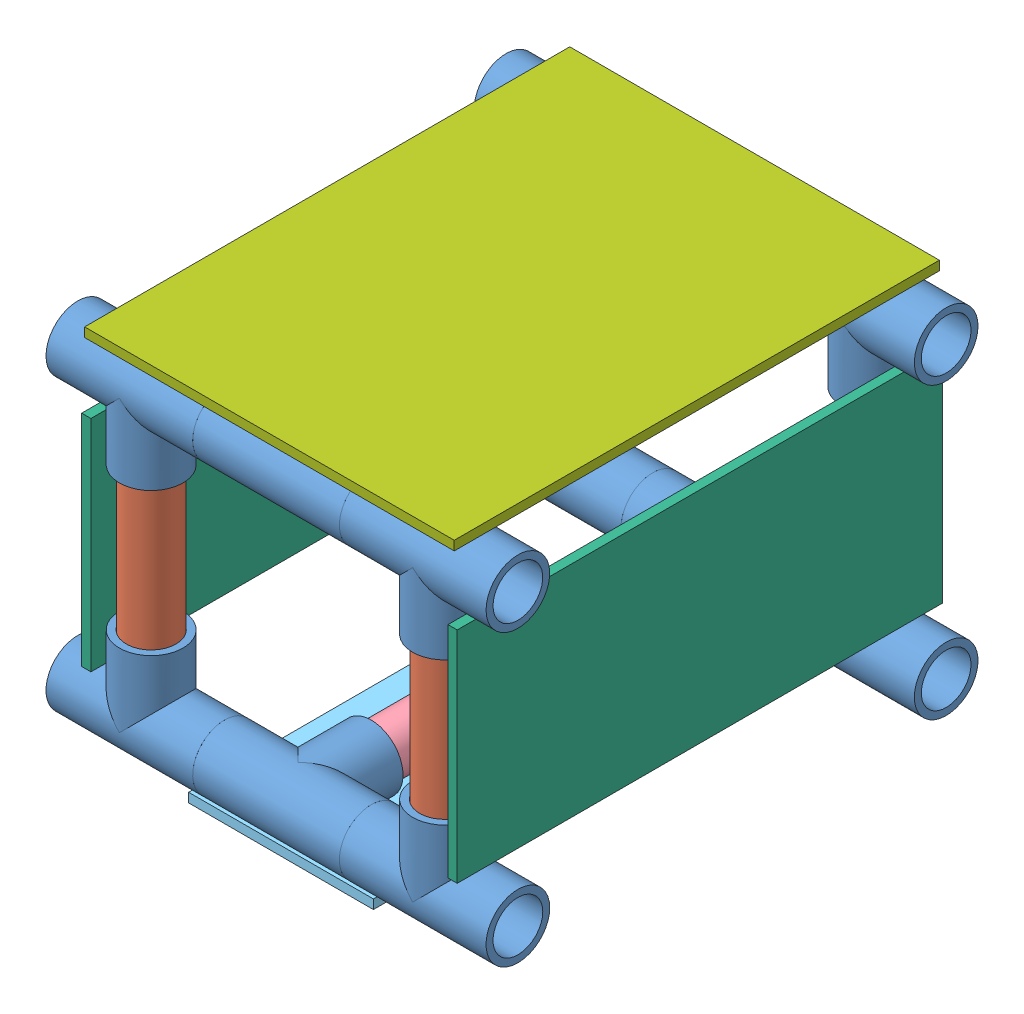
SolidWorks assembly CUBE SAT, configuration Default. Lengths in mm.
Overall size (190.5 160.96 214.93).
32 component instances, 7 part files, 25 mates.
Components (placement in the parent):
- CUBE SATS BASE-1: CUBE SATS BASE [Default] at (166.0773 74.0016 -54.9847) size (190.5 152.96 46.52)
  - 1-2 PVC TEE-1: 1-2 PVC TEE [4880K41] at (-125.8017 -24.3199 166.6691) size (63.5 45.53 27.56)
  - 1-2 PVC TEE-2: 1-2 PVC TEE [4880K41] at (-62.3017 -24.3199 166.6691) x (1 0 0) z (0 -1 0) size (63.5 45.53 27.56)
  - 1-2 PVC TEE-3: 1-2 PVC TEE [4880K41] at (1.1983 -24.3199 166.6691) size (63.5 45.53 27.56)
  - 1-2 PVC TEE-4: 1-2 PVC TEE [4880K41] at (-125.8017 101.0801 166.6691) x (1 0 0) z (0 0 -1) size (63.5 45.53 27.56)
  - 1-2 PVC TEE-5: 1-2 PVC TEE [4880K41] at (-62.3017 101.0801 166.6691) x (1 0 0) z (0 -1 0) size (63.5 45.53 27.56)
  - 1-2 PVC TEE-6: 1-2 PVC TEE [4880K41] at (1.1983 101.0801 166.6691) x (1 0 0) z (0 0 -1) size (63.5 45.53 27.56)
  - 1-2 PVC PIPE 10CM-1: 1-2 PVC PIPE 10CM [48925K91] at (-125.8017 38.3801 166.6691) x (1 0 0) z (0 -1 0) size (21.34 21.34 100)
  - 1-2 PVC PIPE 10CM-2: 1-2 PVC PIPE 10CM [48925K91] at (1.1983 38.3801 166.6691) x (0.837169 0 0.546944) z (0 1 0) size (21.34 21.34 100)
  - 1-2 PVC PIPE 3CM-1: 1-2 PVC PIPE 3CM [48925K91] at (-94.0517 -24.3199 166.6691) x (0 0 1) z (-1 0 0) size (21.34 21.34 38.1)
  - 1-2 PVC PIPE 3CM-2: 1-2 PVC PIPE 3CM [48925K91] at (-30.5517 -24.3199 166.6691) x (0 0 1) z (-1 0 0) size (21.34 21.34 38.1)
  - 1-2 PVC PIPE 3CM-3: 1-2 PVC PIPE 3CM [48925K91] at (-94.0517 101.0801 166.6691) x (0 0 1) z (-1 0 0) size (21.34 21.34 38.1)
  - 1-2 PVC PIPE 3CM-4: 1-2 PVC PIPE 3CM [48925K91] at (-30.5517 101.0801 166.6691) x (0 0 1) z (-1 0 0) size (21.34 21.34 38.1)
- CUBE SATS BASE-2: CUBE SATS BASE [Default] at (41.4738 74.0016 463.7535) x (-1 0 0) z (0 0 -1) size (190.5 152.96 46.52)
  - 1-2 PVC TEE-1: 1-2 PVC TEE [4880K41] at (-125.8017 -24.3199 166.6691) size (63.5 45.53 27.56)
  - 1-2 PVC TEE-2: 1-2 PVC TEE [4880K41] at (-62.3017 -24.3199 166.6691) x (1 0 0) z (0 -1 0) size (63.5 45.53 27.56)
  - 1-2 PVC TEE-3: 1-2 PVC TEE [4880K41] at (1.1983 -24.3199 166.6691) size (63.5 45.53 27.56)
  - 1-2 PVC TEE-4: 1-2 PVC TEE [4880K41] at (-125.8017 101.0801 166.6691) x (1 0 0) z (0 0 -1) size (63.5 45.53 27.56)
  - 1-2 PVC TEE-5: 1-2 PVC TEE [4880K41] at (-62.3017 101.0801 166.6691) x (1 0 0) z (0 -1 0) size (63.5 45.53 27.56)
  - 1-2 PVC TEE-6: 1-2 PVC TEE [4880K41] at (1.1983 101.0801 166.6691) x (1 0 0) z (0 0 -1) size (63.5 45.53 27.56)
  - 1-2 PVC PIPE 10CM-1: 1-2 PVC PIPE 10CM [48925K91] at (-125.8017 38.3801 166.6691) x (1 0 0) z (0 -1 0) size (21.34 21.34 100)
  - 1-2 PVC PIPE 10CM-2: 1-2 PVC PIPE 10CM [48925K91] at (1.1983 38.3801 166.6691) x (0.837169 0 0.546944) z (0 1 0) size (21.34 21.34 100)
  - 1-2 PVC PIPE 3CM-1: 1-2 PVC PIPE 3CM [48925K91] at (-94.0517 -24.3199 166.6691) x (0 0 1) z (-1 0 0) size (21.34 21.34 38.1)
  - 1-2 PVC PIPE 3CM-2: 1-2 PVC PIPE 3CM [48925K91] at (-30.5517 -24.3199 166.6691) x (0 0 1) z (-1 0 0) size (21.34 21.34 38.1)
  - 1-2 PVC PIPE 3CM-3: 1-2 PVC PIPE 3CM [48925K91] at (-94.0517 101.0801 166.6691) x (0 0 1) z (-1 0 0) size (21.34 21.34 38.1)
  - 1-2 PVC PIPE 3CM-4: 1-2 PVC PIPE 3CM [48925K91] at (-30.5517 101.0801 166.6691) x (0 0 1) z (-1 0 0) size (21.34 21.34 38.1)
- 1-2 PVC PIPE 16CM-1: 1-2 PVC PIPE 16CM [48925K91] at (103.7756 175.0818 204.3844) x (-1 0 0) z (0 0 1) size (21.34 21.34 160)
- 1-2 PVC PIPE 16CM-2: 1-2 PVC PIPE 16CM [48925K91] at (103.7756 49.6818 204.3844) size (21.34 21.34 160)
- 20X8-1: 20X8 [Default] at (103.7756 35.9023 204.3844) x (0 0 1) z (1 0 0) size (200 4 80)
- 21X11-1: 21X11 [Default] at (26.4961 112.3818 204.3844) x (0 0 1) z (0 -1 0) size (210 4 95)
- 21X11-2: 21X11 [Default] at (181.0551 112.3818 204.3844) x (0 0 1) z (0 1 0) size (210 4 95)
- 21X16-1: 21X16 [Default] at (103.7756 192.8613 204.3844) x (0 0 -1) z (-1 0 0) size (210 4 160)
Mates (geometry in assembly coordinates):
- Coincident1: coincident anti-aligned: plane of CUBE SATS BASE-1/1-2 PVC TEE-5 through (103.7756 175.0818 124.3844) normal (0 0 1); plane of 1-2 PVC PIPE 16CM-1 through (103.7756 175.0818 124.3844) normal (0 0 -1)
- Concentric1: concentric aligned: cone of CUBE SATS BASE-1/1-2 PVC TEE-5 through (103.7756 175.0818 143.4344) axis (0 0 -1); cylinder of 1-2 PVC PIPE 16CM-1 through (103.7756 175.0818 284.3844) axis (0 0 -1) radius 10.668
- Coincident2: coincident anti-aligned: plane of CUBE SATS BASE-1/1-2 PVC TEE-2 through (103.7756 49.6818 124.3844) normal (0 0 1); plane of 1-2 PVC PIPE 16CM-2 through (103.7756 49.6818 124.3844) normal (0 0 -1)
- Concentric2: concentric aligned: cone of CUBE SATS BASE-1/1-2 PVC TEE-2 through (103.7756 49.6818 143.4344) axis (0 0 -1); cylinder of 1-2 PVC PIPE 16CM-2 through (103.7756 49.6818 284.3844) axis (0 0 -1) radius 10.668
- Coincident3: coincident anti-aligned: plane of CUBE SATS BASE-2/1-2 PVC TEE-5 through (103.7756 175.0818 284.3844) normal (0 0 -1); plane of 1-2 PVC PIPE 16CM-1 through (103.7756 175.0818 284.3844) normal (0 0 1)
- Coincident4: coincident anti-aligned: plane of CUBE SATS BASE-2/1-2 PVC TEE-2 through (103.7756 49.6818 284.3844) normal (0 0 -1); plane of 1-2 PVC PIPE 16CM-2 through (103.7756 49.6818 284.3844) normal (0 0 1)
- Concentric3: concentric anti-aligned: cylinder of CUBE SATS BASE-2/1-2 PVC TEE-5 through (103.7756 175.0818 297.0844) axis (0 0 1) radius 13.7795; cylinder of 1-2 PVC PIPE 16CM-1 through (103.7756 175.0818 284.3844) axis (0 0 -1) radius 10.668
- Concentric4: concentric anti-aligned: cylinder of CUBE SATS BASE-2/1-2 PVC TEE-2 through (103.7756 49.6818 297.0844) axis (0 0 1) radius 13.7795; cylinder of 1-2 PVC PIPE 16CM-2 through (103.7756 49.6818 284.3844) axis (0 0 -1) radius 10.668
- Parallel2: parallel anti-aligned: plane of 21X11-1 through (22.4961 112.3818 204.3844) normal (-1 0 0); plane of assembly through (0 0 0) normal (1 0 0)
- Parallel1: parallel aligned: plane of 21X11-1 through (22.4961 64.8818 309.3844) normal (0 0 1); plane of assembly through (0 0 0) normal (0 0 1)
- Tangent3: tangent anti-aligned: cylinder of CUBE SATS BASE-1/1-2 PVC TEE-1 through (40.2756 49.6818 111.6844) axis (0 -1 0) radius 13.7795; plane of 21X11-1 through (26.4961 112.3818 204.3844) normal (1 0 0)
- Coincident7: coincident aligned: plane of CUBE SATS BASE-1/1-2 PVC PIPE 10CM-1 through (40.2756 112.3818 111.6844) normal (0 -1 0); plane of 21X11-1 through (26.4961 112.3818 204.3844) normal (0 -1 0)
- Coincident8: coincident aligned: plane of 1-2 PVC PIPE 16CM-1 through (103.7756 175.0818 204.3844) normal (0 0 1); plane of 21X11-1
- Parallel3: parallel anti-aligned: plane of 21X11-1 through (22.4961 112.3818 204.3844) normal (-1 0 0); plane of 21X11-2 through (185.0551 112.3818 204.3844) normal (1 0 0)
- Coincident10: coincident aligned: plane of 21X11-1 through (22.4961 64.8818 309.3844) normal (0 0 1); plane of 21X11-2 through (185.0551 159.8818 309.3844) normal (0 0 1)
- Coincident13: coincident aligned: plane of 21X11-1 through (22.4961 64.8818 99.3844) normal (0 -1 0); plane of 21X11-2 through (185.0551 64.8818 99.3844) normal (0 -1 0)
- Tangent4: tangent anti-aligned: cylinder of CUBE SATS BASE-1/1-2 PVC TEE-3 through (167.2756 49.6818 111.6844) axis (0 -1 0) radius 13.7795; plane of 21X11-2 through (181.0551 112.3818 204.3844) normal (-1 0 0)
- Coincident14: coincident aligned: plane of 1-2 PVC PIPE 16CM-1; plane of 21X16-1 through (103.7756 223.2209 204.3844) normal (-1 0 0)
- Coincident16: coincident anti-aligned: plane of 1-2 PVC PIPE 16CM-1 through (103.7756 175.0818 204.3844) normal (0 0 1); plane of 21X16-1
- Coincident17: coincident anti-aligned: plane of 1-2 PVC PIPE 16CM-1; plane of 20X8-1 through (103.7756 35.9023 204.3844) normal (1 0 0)
- Coincident18: coincident aligned: plane of 1-2 PVC PIPE 16CM-1 through (103.7756 175.0818 204.3844) normal (0 0 1); plane of 20X8-1
- Tangent7: tangent anti-aligned: cylinder of CUBE SATS BASE-2/1-2 PVC TEE-2 through (103.7756 49.6818 297.0844) axis (0 0 1) radius 13.7795; plane of 20X8-1 through (103.7756 35.9023 204.3844) normal (0 1 0)
- Perpendicular1: perpendicular: plane of 21X11-2 through (185.0551 159.8818 99.3844) normal (0 1 0); plane of 21X16-1 through (23.7756 219.2209 99.3844) normal (0 0 -1)
- Parallel6: parallel aligned: plane of ? through (103.7756 223.2209 204.3844) normal (0 1 0)
- Tangent8: tangent anti-aligned: cylinder of CUBE SATS BASE-1/1-2 PVC TEE-5 through (103.7756 175.0818 111.6844) axis (0 0 -1) radius 13.7795; plane of 21X16-1 through (103.7756 188.8613 204.3844) normal (0 -1 0)
